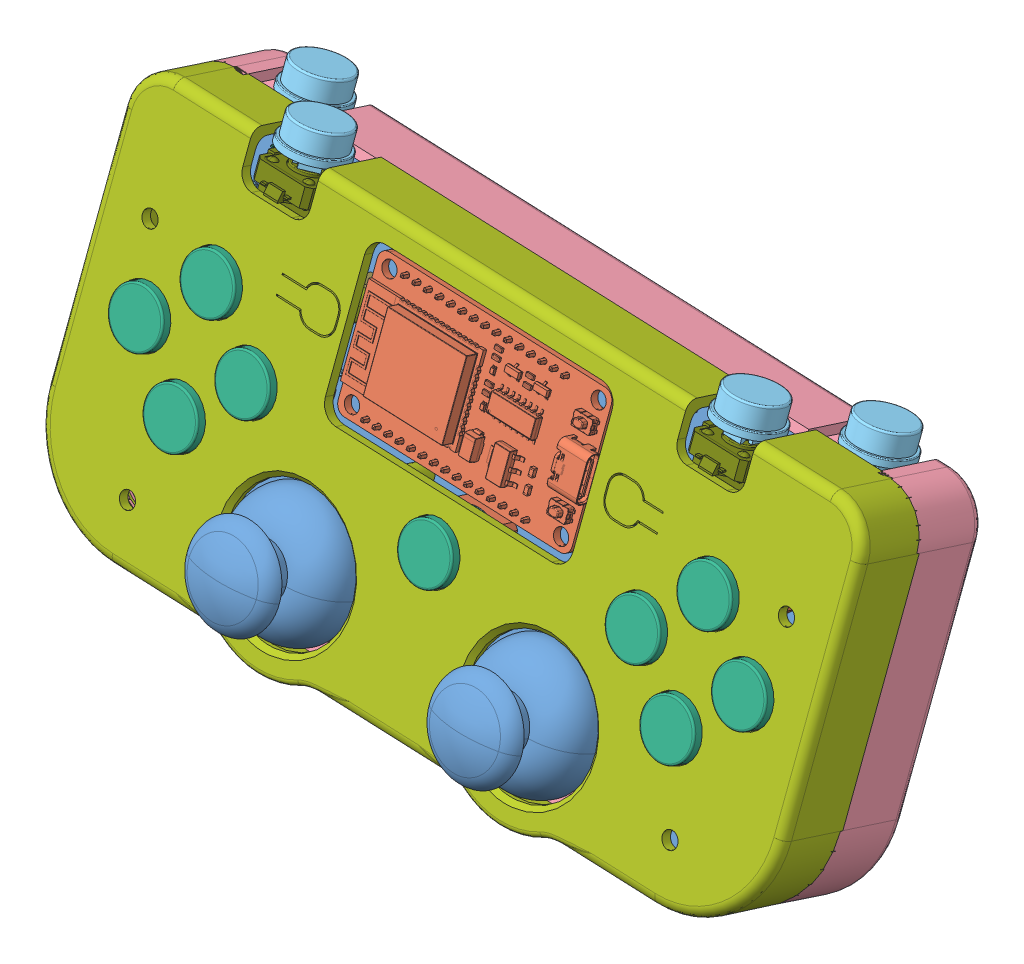
SolidWorks assembly controller, configuration Default. Lengths in mm.
Overall size (166.67 96.35 70.51).
213 component instances, 26 part files, 78 mates.
Components (placement in the parent):
- controller.step-1: controller.step [Default] at (25.4775 3.2443 108.305) x (0.999315 -0.03652 0.006033) z (0.005555 0.30909 0.951017) size (158.62 75.66 29.81)
  - Board.step-1: Board.step [Default] at origin size (158.62 74.17 0.41)
    - Open CASCADE STEP translator 7.5 1.1.1.step-1: Open CASCADE STEP translator 7.5 1.1.1.step [Default] at (0 0 -0.4115) size (158.62 74.17 0.41)
  - SW11.step-1: SW11.step [Default] at origin size (12 13.8 8.01)
    - Switch_Omron_B3F-4000_eec.step-1: Switch_Omron_B3F-4000_eec.step [Default] at (92.7295 35.2468 2.4624) x (0 1 0) z (0 0 1) size (13.8 12 8.01)
      - Omron B3F-4000 1.step-1: Omron B3F-4000 1.step [Default] at (3.1026 -5.4513 -0.4613) size (12 12 5.5)
      - Omron B3F-4000 2.step-1: Omron B3F-4000 2.step [Default] at (3.1026 -5.4513 2.5387) x (-1 0 0) z (0 0 1) size (11 11 0.5)
      - Omron B3F-4000 3.step-1: Omron B3F-4000 3.step [Default] at (3.1026 -5.4513 4.0387) x (1 0 0) z (0 0 -1) size (7.1 7.1 1.5)
      - Omron B3F-4000 4.step-1: Omron B3F-4000 4.step [Default] at (9.5526 -2.4513 -1.9613) x (1 0 0) z (0 -1 0) size (0.9 4 1)
      - Omron B3F-4000 4.step-2: Omron B3F-4000 4.step [Default] at (9.5526 -7.4513 -1.9613) x (1 0 0) z (0 -1 0) size (0.9 4 1)
      - Omron B3F-4000 4_MIR.step-1: Omron B3F-4000 4_MIR.step [Default] at (-3.3474 -2.4513 -1.9613) x (-1 0 0) z (0 1 0) size (0.9 4 1)
      - Omron B3F-4000 4_MIR.step-2: Omron B3F-4000 4_MIR.step [Default] at (-3.3474 -7.4513 -1.9613) x (-1 0 0) z (0 1 0) size (0.9 4 1)
      - Omron B3F-4000 5.step-1: Omron B3F-4000 5.step [Default] at (7.6026 -0.9513 3.0387) size (1.5 1.5 1.2)
      - Omron B3F-4000 5_MIR2.step-1: Omron B3F-4000 5_MIR2.step [Default] at (7.6026 -9.9513 3.0387) x (1 0 0) z (0 0 -1) size (1.5 1.5 1.2)
      - Omron B3F-4000 5_MIR3.step-1: Omron B3F-4000 5_MIR3.step [Default] at (-1.3974 -0.9513 3.0387) x (-1 0 0) z (0 0 -1) size (1.5 1.5 1.2)
      - Omron B3F-4000 5_MIR2_MIR.step-1: Omron B3F-4000 5_MIR2_MIR.step [Default] at (-1.3974 -9.9513 3.0387) x (-1 0 0) z (0 0 1) size (1.5 1.5 1.2)
      - Omron.step-1: Omron.step [Default] at (3.0502 -5.7952 4.0387) size (2.99 0.61 0.02)
  - SW9.step-1: SW9.step [Default] at origin size (6 6 4.5)
    - 7098939168.step-1: 7098939168.step [Default] at (64.389 64.262 0) size (6 6 4.5)
      - Extruded.step-1: Extruded.step [Default] at origin size (6 6 4.5)
  - SW10.step-1: SW10.step [Default] at origin size (6 6 4.5)
    - 7098939168.step-1: 7098939168.step [Default] at (131.953 64.262 0) size (6 6 4.5)
      - Extruded.step-1: Extruded.step [Default] at origin size (6 6 4.5)
  - C5.step-1: C5.step [Default] at origin size (3.81 2.54 11.66)
    - 7094425376.step-1: 7094425376.step [Default] at (34.6711 68.58 -7) size (0.51 0.51 7)
      - Extruded-0.step-1: Extruded-0.step [Default] at origin size (0.51 0.51 7)
    - 7094425376.step-2: 7094425376.step [Default] at (32.1311 68.5801 -7) size (0.51 0.51 7)
      - Extruded-0.step-1: Extruded-0.step [Default] at origin size (0.51 0.51 7)
    - 7098940608.step-1: 7098940608.step [Default] at (33.401 68.58 0) size (3.81 2.54 4.66)
      - Extruded-1.step-1: Extruded-1.step [Default] at origin size (3.81 2.54 4.66)
  - C6.step-1: C6.step [Default] at origin size (3.81 2.54 11.66)
    - 7094425376.step-1: 7094425376.step [Default] at (165.3541 67.31 -7) size (0.51 0.51 7)
      - Extruded-0.step-1: Extruded-0.step [Default] at origin size (0.51 0.51 7)
    - 7094425376.step-2: 7094425376.step [Default] at (162.8141 67.3101 -7) size (0.51 0.51 7)
      - Extruded-0.step-1: Extruded-0.step [Default] at origin size (0.51 0.51 7)
    - 7098940608.step-1: 7098940608.step [Default] at (164.084 67.31 0) size (3.81 2.54 4.66)
      - Extruded-1.step-1: Extruded-1.step [Default] at origin size (3.81 2.54 4.66)
  - S4.step-1: S4.step [Default] at origin size (13.1 13.3 18.3)
    - 6508629744.step-1: 6508629744.step [Default] at (160.742 77.978 -0.4115) x (0 -1 0) z (1 0 0) size (13.3 18.3 13.1)
  - S3.step-1: S3.step [Default] at origin size (13.1 13.3 18.3)
    - 6508631584.step-1: 6508631584.step [Default] at (146.344 77.978 0) x (0 -1 0) z (-1 0 0) size (13.3 18.3 13.1)
  - S2.step-1: S2.step [Default] at origin size (13.1 13.3 18.3)
    - 6508631584.step-1: 6508631584.step [Default] at (49.744 77.978 0) x (0 -1 0) z (-1 0 0) size (13.3 18.3 13.1)
  - S1.step-1: S1.step [Default] at origin size (13.1 13.3 18.3)
    - 6508629744.step-1: 6508629744.step [Default] at (35.346 77.978 -0.4115) x (0 -1 0) z (1 0 0) size (13.3 18.3 13.1)
  - C4.step-1: C4.step [Default] at origin size (4.49 4.49 11.66)
    - 7094425376.step-1: 7094425376.step [Default] at (30.4371 33.138 -7) size (0.51 0.51 7)
      - Extruded-0.step-1: Extruded-0.step [Default] at origin size (0.51 0.51 7)
    - 7094425376.step-2: 7094425376.step [Default] at (28.6411 34.9341 -7) size (0.51 0.51 7)
      - Extruded-0.step-1: Extruded-0.step [Default] at origin size (0.51 0.51 7)
    - 7094424896.step-1: 7094424896.step [Default] at (29.5392 34.036 0) size (4.49 4.49 4.66)
      - Extruded-2.step-1: Extruded-2.step [Default] at origin size (4.49 4.49 4.66)
  - C3.step-1: C3.step [Default] at origin size (4.49 4.49 11.66)
    - 7094425376.step-1: 7094425376.step [Default] at (166.7082 33.9179 -7) size (0.51 0.51 7)
      - Extruded-0.step-1: Extruded-0.step [Default] at origin size (0.51 0.51 7)
    - 7094425376.step-2: 7094425376.step [Default] at (164.9122 32.1219 -7) size (0.51 0.51 7)
      - Extruded-0.step-1: Extruded-0.step [Default] at origin size (0.51 0.51 7)
    - 7098938768.step-1: 7098938768.step [Default] at (165.8102 33.02 0) size (4.49 4.49 4.66)
      - Extruded-3.step-1: Extruded-3.step [Default] at origin size (4.49 4.49 4.66)
  - C2.step-1: C2.step [Default] at origin size (4.49 4.49 11.66)
    - 7094425376.step-1: 7094425376.step [Default] at (55.4293 60.9781 -7) size (0.51 0.51 7)
      - Extruded-0.step-1: Extruded-0.step [Default] at origin size (0.51 0.51 7)
    - 7094425376.step-2: 7094425376.step [Default] at (57.2253 59.182 -7) size (0.51 0.51 7)
      - Extruded-0.step-1: Extruded-0.step [Default] at origin size (0.51 0.51 7)
    - 7094424896.step-1: 7094424896.step [Default] at (56.3272 60.08 0) size (4.49 4.49 4.66)
      - Extruded-2.step-1: Extruded-2.step [Default] at origin size (4.49 4.49 4.66)
  - C1.step-1: C1.step [Default] at origin size (4.49 4.49 11.66)
    - 7094425376.step-1: 7094425376.step [Default] at (139.5122 58.4111 -7) size (0.51 0.51 7)
      - Extruded-0.step-1: Extruded-0.step [Default] at origin size (0.51 0.51 7)
    - 7094425376.step-2: 7094425376.step [Default] at (141.3083 60.2071 -7) size (0.51 0.51 7)
      - Extruded-0.step-1: Extruded-0.step [Default] at origin size (0.51 0.51 7)
    - 7098938768.step-1: 7098938768.step [Default] at (140.4102 59.309 0) size (4.49 4.49 4.66)
      - Extruded-3.step-1: Extruded-3.step [Default] at origin size (4.49 4.49 4.66)
  - SW1.step-1: SW1.step [Default] at origin size (18.24 18.24 8.01)
    - Switch_Omron_B3F-4000_eec.step-1: Switch_Omron_B3F-4000_eec.step [Default] at (48.6404 48.2596 2.4624) x (0.707107 0.707107 0) z (0 0 1) size (13.8 12 8.01)
      - Omron B3F-4000 1.step-1: Omron B3F-4000 1.step [Default] at (3.1026 -5.4513 -0.4613) size (12 12 5.5)
      - Omron B3F-4000 2.step-1: Omron B3F-4000 2.step [Default] at (3.1026 -5.4513 2.5387) x (-1 0 0) z (0 0 1) size (11 11 0.5)
      - Omron B3F-4000 3.step-1: Omron B3F-4000 3.step [Default] at (3.1026 -5.4513 4.0387) x (1 0 0) z (0 0 -1) size (7.1 7.1 1.5)
      - Omron B3F-4000 4.step-1: Omron B3F-4000 4.step [Default] at (9.5526 -2.4513 -1.9613) x (1 0 0) z (0 -1 0) size (0.9 4 1)
      - Omron B3F-4000 4.step-2: Omron B3F-4000 4.step [Default] at (9.5526 -7.4513 -1.9613) x (1 0 0) z (0 -1 0) size (0.9 4 1)
      - Omron B3F-4000 4_MIR.step-1: Omron B3F-4000 4_MIR.step [Default] at (-3.3474 -2.4513 -1.9613) x (-1 0 0) z (0 1 0) size (0.9 4 1)
      - Omron B3F-4000 4_MIR.step-2: Omron B3F-4000 4_MIR.step [Default] at (-3.3474 -7.4513 -1.9613) x (-1 0 0) z (0 1 0) size (0.9 4 1)
      - Omron B3F-4000 5.step-1: Omron B3F-4000 5.step [Default] at (7.6026 -0.9513 3.0387) size (1.5 1.5 1.2)
      - Omron B3F-4000 5_MIR2.step-1: Omron B3F-4000 5_MIR2.step [Default] at (7.6026 -9.9513 3.0387) x (1 0 0) z (0 0 -1) size (1.5 1.5 1.2)
      - Omron B3F-4000 5_MIR3.step-1: Omron B3F-4000 5_MIR3.step [Default] at (-1.3974 -0.9513 3.0387) x (-1 0 0) z (0 0 -1) size (1.5 1.5 1.2)
      - Omron B3F-4000 5_MIR2_MIR.step-1: Omron B3F-4000 5_MIR2_MIR.step [Default] at (-1.3974 -9.9513 3.0387) x (-1 0 0) z (0 0 1) size (1.5 1.5 1.2)
      - Omron.step-1: Omron.step [Default] at (3.0502 -5.7952 4.0387) size (2.99 0.61 0.02)
  - SW2.step-1: SW2.step [Default] at origin size (18.24 18.24 8.01)
    - Switch_Omron_B3F-4000_eec.step-1: Switch_Omron_B3F-4000_eec.step [Default] at (36.8294 60.0706 2.4624) x (0.707107 0.707107 0) z (0 0 1) size (13.8 12 8.01)
      - Omron B3F-4000 1.step-1: Omron B3F-4000 1.step [Default] at (3.1026 -5.4513 -0.4613) size (12 12 5.5)
      - Omron B3F-4000 2.step-1: Omron B3F-4000 2.step [Default] at (3.1026 -5.4513 2.5387) x (-1 0 0) z (0 0 1) size (11 11 0.5)
      - Omron B3F-4000 3.step-1: Omron B3F-4000 3.step [Default] at (3.1026 -5.4513 4.0387) x (1 0 0) z (0 0 -1) size (7.1 7.1 1.5)
      - Omron B3F-4000 4.step-1: Omron B3F-4000 4.step [Default] at (9.5526 -2.4513 -1.9613) x (1 0 0) z (0 -1 0) size (0.9 4 1)
      - Omron B3F-4000 4.step-2: Omron B3F-4000 4.step [Default] at (9.5526 -7.4513 -1.9613) x (1 0 0) z (0 -1 0) size (0.9 4 1)
      - Omron B3F-4000 4_MIR.step-1: Omron B3F-4000 4_MIR.step [Default] at (-3.3474 -2.4513 -1.9613) x (-1 0 0) z (0 1 0) size (0.9 4 1)
      - Omron B3F-4000 4_MIR.step-2: Omron B3F-4000 4_MIR.step [Default] at (-3.3474 -7.4513 -1.9613) x (-1 0 0) z (0 1 0) size (0.9 4 1)
      - Omron B3F-4000 5.step-1: Omron B3F-4000 5.step [Default] at (7.6026 -0.9513 3.0387) size (1.5 1.5 1.2)
      - Omron B3F-4000 5_MIR2.step-1: Omron B3F-4000 5_MIR2.step [Default] at (7.6026 -9.9513 3.0387) x (1 0 0) z (0 0 -1) size (1.5 1.5 1.2)
      - Omron B3F-4000 5_MIR3.step-1: Omron B3F-4000 5_MIR3.step [Default] at (-1.3974 -0.9513 3.0387) x (-1 0 0) z (0 0 -1) size (1.5 1.5 1.2)
      - Omron B3F-4000 5_MIR2_MIR.step-1: Omron B3F-4000 5_MIR2_MIR.step [Default] at (-1.3974 -9.9513 3.0387) x (-1 0 0) z (0 0 1) size (1.5 1.5 1.2)
      - Omron.step-1: Omron.step [Default] at (3.0502 -5.7952 4.0387) size (2.99 0.61 0.02)
  - SW3.step-1: SW3.step [Default] at origin size (18.24 18.24 8.01)
    - Switch_Omron_B3F-4000_eec.step-1: Switch_Omron_B3F-4000_eec.step [Default] at (25.0184 48.2596 2.4624) x (0.707107 0.707107 0) z (0 0 1) size (13.8 12 8.01)
      - Omron B3F-4000 1.step-1: Omron B3F-4000 1.step [Default] at (3.1026 -5.4513 -0.4613) size (12 12 5.5)
      - Omron B3F-4000 2.step-1: Omron B3F-4000 2.step [Default] at (3.1026 -5.4513 2.5387) x (-1 0 0) z (0 0 1) size (11 11 0.5)
      - Omron B3F-4000 3.step-1: Omron B3F-4000 3.step [Default] at (3.1026 -5.4513 4.0387) x (1 0 0) z (0 0 -1) size (7.1 7.1 1.5)
      - Omron B3F-4000 4.step-1: Omron B3F-4000 4.step [Default] at (9.5526 -2.4513 -1.9613) x (1 0 0) z (0 -1 0) size (0.9 4 1)
      - Omron B3F-4000 4.step-2: Omron B3F-4000 4.step [Default] at (9.5526 -7.4513 -1.9613) x (1 0 0) z (0 -1 0) size (0.9 4 1)
      - Omron B3F-4000 4_MIR.step-1: Omron B3F-4000 4_MIR.step [Default] at (-3.3474 -2.4513 -1.9613) x (-1 0 0) z (0 1 0) size (0.9 4 1)
      - Omron B3F-4000 4_MIR.step-2: Omron B3F-4000 4_MIR.step [Default] at (-3.3474 -7.4513 -1.9613) x (-1 0 0) z (0 1 0) size (0.9 4 1)
      - Omron B3F-4000 5.step-1: Omron B3F-4000 5.step [Default] at (7.6026 -0.9513 3.0387) size (1.5 1.5 1.2)
      - Omron B3F-4000 5_MIR2.step-1: Omron B3F-4000 5_MIR2.step [Default] at (7.6026 -9.9513 3.0387) x (1 0 0) z (0 0 -1) size (1.5 1.5 1.2)
      - Omron B3F-4000 5_MIR3.step-1: Omron B3F-4000 5_MIR3.step [Default] at (-1.3974 -0.9513 3.0387) x (-1 0 0) z (0 0 -1) size (1.5 1.5 1.2)
      - Omron B3F-4000 5_MIR2_MIR.step-1: Omron B3F-4000 5_MIR2_MIR.step [Default] at (-1.3974 -9.9513 3.0387) x (-1 0 0) z (0 0 1) size (1.5 1.5 1.2)
      - Omron.step-1: Omron.step [Default] at (3.0502 -5.7952 4.0387) size (2.99 0.61 0.02)
  - SW4.step-1: SW4.step [Default] at origin size (18.24 18.24 8.01)
    - Switch_Omron_B3F-4000_eec.step-1: Switch_Omron_B3F-4000_eec.step [Default] at (36.8294 36.4486 2.4624) x (0.707107 0.707107 0) z (0 0 1) size (13.8 12 8.01)
      - Omron B3F-4000 1.step-1: Omron B3F-4000 1.step [Default] at (3.1026 -5.4513 -0.4613) size (12 12 5.5)
      - Omron B3F-4000 2.step-1: Omron B3F-4000 2.step [Default] at (3.1026 -5.4513 2.5387) x (-1 0 0) z (0 0 1) size (11 11 0.5)
      - Omron B3F-4000 3.step-1: Omron B3F-4000 3.step [Default] at (3.1026 -5.4513 4.0387) x (1 0 0) z (0 0 -1) size (7.1 7.1 1.5)
      - Omron B3F-4000 4.step-1: Omron B3F-4000 4.step [Default] at (9.5526 -2.4513 -1.9613) x (1 0 0) z (0 -1 0) size (0.9 4 1)
      - Omron B3F-4000 4.step-2: Omron B3F-4000 4.step [Default] at (9.5526 -7.4513 -1.9613) x (1 0 0) z (0 -1 0) size (0.9 4 1)
      - Omron B3F-4000 4_MIR.step-1: Omron B3F-4000 4_MIR.step [Default] at (-3.3474 -2.4513 -1.9613) x (-1 0 0) z (0 1 0) size (0.9 4 1)
      - Omron B3F-4000 4_MIR.step-2: Omron B3F-4000 4_MIR.step [Default] at (-3.3474 -7.4513 -1.9613) x (-1 0 0) z (0 1 0) size (0.9 4 1)
      - Omron B3F-4000 5.step-1: Omron B3F-4000 5.step [Default] at (7.6026 -0.9513 3.0387) size (1.5 1.5 1.2)
      - Omron B3F-4000 5_MIR2.step-1: Omron B3F-4000 5_MIR2.step [Default] at (7.6026 -9.9513 3.0387) x (1 0 0) z (0 0 -1) size (1.5 1.5 1.2)
      - Omron B3F-4000 5_MIR3.step-1: Omron B3F-4000 5_MIR3.step [Default] at (-1.3974 -0.9513 3.0387) x (-1 0 0) z (0 0 -1) size (1.5 1.5 1.2)
      - Omron B3F-4000 5_MIR2_MIR.step-1: Omron B3F-4000 5_MIR2_MIR.step [Default] at (-1.3974 -9.9513 3.0387) x (-1 0 0) z (0 0 1) size (1.5 1.5 1.2)
      - Omron.step-1: Omron.step [Default] at (3.0502 -5.7952 4.0387) size (2.99 0.61 0.02)
  - SW8.step-1: SW8.step [Default] at origin size (18.24 18.24 8.01)
    - Switch_Omron_B3F-4000_eec.step-1: Switch_Omron_B3F-4000_eec.step [Default] at (147.1924 36.4486 2.4624) x (0.707107 0.707107 0) z (0 0 1) size (13.8 12 8.01)
      - Omron B3F-4000 1.step-1: Omron B3F-4000 1.step [Default] at (3.1026 -5.4513 -0.4613) size (12 12 5.5)
      - Omron B3F-4000 2.step-1: Omron B3F-4000 2.step [Default] at (3.1026 -5.4513 2.5387) x (-1 0 0) z (0 0 1) size (11 11 0.5)
      - Omron B3F-4000 3.step-1: Omron B3F-4000 3.step [Default] at (3.1026 -5.4513 4.0387) x (1 0 0) z (0 0 -1) size (7.1 7.1 1.5)
      - Omron B3F-4000 4.step-1: Omron B3F-4000 4.step [Default] at (9.5526 -2.4513 -1.9613) x (1 0 0) z (0 -1 0) size (0.9 4 1)
      - Omron B3F-4000 4.step-2: Omron B3F-4000 4.step [Default] at (9.5526 -7.4513 -1.9613) x (1 0 0) z (0 -1 0) size (0.9 4 1)
      - Omron B3F-4000 4_MIR.step-1: Omron B3F-4000 4_MIR.step [Default] at (-3.3474 -2.4513 -1.9613) x (-1 0 0) z (0 1 0) size (0.9 4 1)
      - Omron B3F-4000 4_MIR.step-2: Omron B3F-4000 4_MIR.step [Default] at (-3.3474 -7.4513 -1.9613) x (-1 0 0) z (0 1 0) size (0.9 4 1)
      - Omron B3F-4000 5.step-1: Omron B3F-4000 5.step [Default] at (7.6026 -0.9513 3.0387) size (1.5 1.5 1.2)
      - Omron B3F-4000 5_MIR2.step-1: Omron B3F-4000 5_MIR2.step [Default] at (7.6026 -9.9513 3.0387) x (1 0 0) z (0 0 -1) size (1.5 1.5 1.2)
      - Omron B3F-4000 5_MIR3.step-1: Omron B3F-4000 5_MIR3.step [Default] at (-1.3974 -0.9513 3.0387) x (-1 0 0) z (0 0 -1) size (1.5 1.5 1.2)
      - Omron B3F-4000 5_MIR2_MIR.step-1: Omron B3F-4000 5_MIR2_MIR.step [Default] at (-1.3974 -9.9513 3.0387) x (-1 0 0) z (0 0 1) size (1.5 1.5 1.2)
      - Omron.step-1: Omron.step [Default] at (3.0502 -5.7952 4.0387) size (2.99 0.61 0.02)
  - SW7.step-1: SW7.step [Default] at origin size (18.24 18.24 8.01)
    - Switch_Omron_B3F-4000_eec.step-1: Switch_Omron_B3F-4000_eec.step [Default] at (135.3813 48.2596 2.4624) x (0.707107 0.707107 0) z (0 0 1) size (13.8 12 8.01)
      - Omron B3F-4000 1.step-1: Omron B3F-4000 1.step [Default] at (3.1026 -5.4513 -0.4613) size (12 12 5.5)
      - Omron B3F-4000 2.step-1: Omron B3F-4000 2.step [Default] at (3.1026 -5.4513 2.5387) x (-1 0 0) z (0 0 1) size (11 11 0.5)
      - Omron B3F-4000 3.step-1: Omron B3F-4000 3.step [Default] at (3.1026 -5.4513 4.0387) x (1 0 0) z (0 0 -1) size (7.1 7.1 1.5)
      - Omron B3F-4000 4.step-1: Omron B3F-4000 4.step [Default] at (9.5526 -2.4513 -1.9613) x (1 0 0) z (0 -1 0) size (0.9 4 1)
      - Omron B3F-4000 4.step-2: Omron B3F-4000 4.step [Default] at (9.5526 -7.4513 -1.9613) x (1 0 0) z (0 -1 0) size (0.9 4 1)
      - Omron B3F-4000 4_MIR.step-1: Omron B3F-4000 4_MIR.step [Default] at (-3.3474 -2.4513 -1.9613) x (-1 0 0) z (0 1 0) size (0.9 4 1)
      - Omron B3F-4000 4_MIR.step-2: Omron B3F-4000 4_MIR.step [Default] at (-3.3474 -7.4513 -1.9613) x (-1 0 0) z (0 1 0) size (0.9 4 1)
      - Omron B3F-4000 5.step-1: Omron B3F-4000 5.step [Default] at (7.6026 -0.9513 3.0387) size (1.5 1.5 1.2)
      - Omron B3F-4000 5_MIR2.step-1: Omron B3F-4000 5_MIR2.step [Default] at (7.6026 -9.9513 3.0387) x (1 0 0) z (0 0 -1) size (1.5 1.5 1.2)
      - Omron B3F-4000 5_MIR3.step-1: Omron B3F-4000 5_MIR3.step [Default] at (-1.3974 -0.9513 3.0387) x (-1 0 0) z (0 0 -1) size (1.5 1.5 1.2)
      - Omron B3F-4000 5_MIR2_MIR.step-1: Omron B3F-4000 5_MIR2_MIR.step [Default] at (-1.3974 -9.9513 3.0387) x (-1 0 0) z (0 0 1) size (1.5 1.5 1.2)
      - Omron.step-1: Omron.step [Default] at (3.0502 -5.7952 4.0387) size (2.99 0.61 0.02)
  - SW6.step-1: SW6.step [Default] at origin size (18.24 18.24 8.01)
    - Switch_Omron_B3F-4000_eec.step-1: Switch_Omron_B3F-4000_eec.step [Default] at (147.1924 60.0706 2.4624) x (0.707107 0.707107 0) z (0 0 1) size (13.8 12 8.01)
      - Omron B3F-4000 1.step-1: Omron B3F-4000 1.step [Default] at (3.1026 -5.4513 -0.4613) size (12 12 5.5)
      - Omron B3F-4000 2.step-1: Omron B3F-4000 2.step [Default] at (3.1026 -5.4513 2.5387) x (-1 0 0) z (0 0 1) size (11 11 0.5)
      - Omron B3F-4000 3.step-1: Omron B3F-4000 3.step [Default] at (3.1026 -5.4513 4.0387) x (1 0 0) z (0 0 -1) size (7.1 7.1 1.5)
      - Omron B3F-4000 4.step-1: Omron B3F-4000 4.step [Default] at (9.5526 -2.4513 -1.9613) x (1 0 0) z (0 -1 0) size (0.9 4 1)
      - Omron B3F-4000 4.step-2: Omron B3F-4000 4.step [Default] at (9.5526 -7.4513 -1.9613) x (1 0 0) z (0 -1 0) size (0.9 4 1)
      - Omron B3F-4000 4_MIR.step-1: Omron B3F-4000 4_MIR.step [Default] at (-3.3474 -2.4513 -1.9613) x (-1 0 0) z (0 1 0) size (0.9 4 1)
      - Omron B3F-4000 4_MIR.step-2: Omron B3F-4000 4_MIR.step [Default] at (-3.3474 -7.4513 -1.9613) x (-1 0 0) z (0 1 0) size (0.9 4 1)
      - Omron B3F-4000 5.step-1: Omron B3F-4000 5.step [Default] at (7.6026 -0.9513 3.0387) size (1.5 1.5 1.2)
      - Omron B3F-4000 5_MIR2.step-1: Omron B3F-4000 5_MIR2.step [Default] at (7.6026 -9.9513 3.0387) x (1 0 0) z (0 0 -1) size (1.5 1.5 1.2)
      - Omron B3F-4000 5_MIR3.step-1: Omron B3F-4000 5_MIR3.step [Default] at (-1.3974 -0.9513 3.0387) x (-1 0 0) z (0 0 -1) size (1.5 1.5 1.2)
      - Omron B3F-4000 5_MIR2_MIR.step-1: Omron B3F-4000 5_MIR2_MIR.step [Default] at (-1.3974 -9.9513 3.0387) x (-1 0 0) z (0 0 1) size (1.5 1.5 1.2)
      - Omron.step-1: Omron.step [Default] at (3.0502 -5.7952 4.0387) size (2.99 0.61 0.02)
  - SW5.step-1: SW5.step [Default] at origin size (18.24 18.24 8.01)
    - Switch_Omron_B3F-4000_eec.step-1: Switch_Omron_B3F-4000_eec.step [Default] at (159.0034 48.2596 2.4624) x (0.707107 0.707107 0) z (0 0 1) size (13.8 12 8.01)
      - Omron B3F-4000 1.step-1: Omron B3F-4000 1.step [Default] at (3.1026 -5.4513 -0.4613) size (12 12 5.5)
      - Omron B3F-4000 2.step-1: Omron B3F-4000 2.step [Default] at (3.1026 -5.4513 2.5387) x (-1 0 0) z (0 0 1) size (11 11 0.5)
      - Omron B3F-4000 3.step-1: Omron B3F-4000 3.step [Default] at (3.1026 -5.4513 4.0387) x (1 0 0) z (0 0 -1) size (7.1 7.1 1.5)
      - Omron B3F-4000 4.step-1: Omron B3F-4000 4.step [Default] at (9.5526 -2.4513 -1.9613) x (1 0 0) z (0 -1 0) size (0.9 4 1)
      - Omron B3F-4000 4.step-2: Omron B3F-4000 4.step [Default] at (9.5526 -7.4513 -1.9613) x (1 0 0) z (0 -1 0) size (0.9 4 1)
      - Omron B3F-4000 4_MIR.step-1: Omron B3F-4000 4_MIR.step [Default] at (-3.3474 -2.4513 -1.9613) x (-1 0 0) z (0 1 0) size (0.9 4 1)
      - Omron B3F-4000 4_MIR.step-2: Omron B3F-4000 4_MIR.step [Default] at (-3.3474 -7.4513 -1.9613) x (-1 0 0) z (0 1 0) size (0.9 4 1)
      - Omron B3F-4000 5.step-1: Omron B3F-4000 5.step [Default] at (7.6026 -0.9513 3.0387) size (1.5 1.5 1.2)
      - Omron B3F-4000 5_MIR2.step-1: Omron B3F-4000 5_MIR2.step [Default] at (7.6026 -9.9513 3.0387) x (1 0 0) z (0 0 -1) size (1.5 1.5 1.2)
      - Omron B3F-4000 5_MIR3.step-1: Omron B3F-4000 5_MIR3.step [Default] at (-1.3974 -0.9513 3.0387) x (-1 0 0) z (0 0 -1) size (1.5 1.5 1.2)
      - Omron B3F-4000 5_MIR2_MIR.step-1: Omron B3F-4000 5_MIR2_MIR.step [Default] at (-1.3974 -9.9513 3.0387) x (-1 0 0) z (0 0 1) size (1.5 1.5 1.2)
      - Omron.step-1: Omron.step [Default] at (3.0502 -5.7952 4.0387) size (2.99 0.61 0.02)
- COM-09032-1: COM-09032 [Default] at (97.4277 22.5889 101.5976) x (0.999315 -0.03652 0.006033) z (-0.036596 -0.950331 0.309081) size (26.67 34.67 27.62)
- COM-09032-2: COM-09032 [Default] at (151.2136 20.6099 101.9266) x (0.999315 -0.03652 0.006033) z (-0.036596 -0.950331 0.309081) size (26.67 34.67 27.62)
- esp32_30pin-1: esp32_30pin [По умолчанию] at (148.2005 52.2986 104.8892) x (0.036596 0.950331 -0.309081) z (0.005555 0.30909 0.951017) size (29 52.96 13.53)
- powerboost 1000c.f3d v3-1: powerboost 1000c.f3d v3 [Default] at (151.8493 9.8112 109.6265) x (0.036596 0.950331 -0.309081) z (-0.005555 -0.30909 -0.951017) size (36.64 22.86 4.38)
- Bottom_plate_R3-1: Bottom_plate_R3 [Default] at (45.1984 24.5346 86.1165) x (0.999315 -0.03652 0.006033) z (-0.036596 -0.950331 0.309081) size (163.63 15.6 81.83)
- 12mm Push Button Cap-1: 12mm Push Button Cap [Default] at (179.9154 32.315 103.4225) x (0.640311 -0.731594 0.234035) z (-0.768096 -0.607647 0.201977) size (13 8.2 13)
- 12mm Push Button Cap-2: 12mm Push Button Cap [Default] at (180.7799 54.7638 96.1214) x (0.640311 -0.731594 0.234035) z (-0.768096 -0.607647 0.201977) size (13 8.2 13)
- 12mm Push Button Cap-3: 12mm Push Button Cap [Default] at (168.5447 43.9708 99.7007) x (0.640311 -0.731594 0.234035) z (-0.768096 -0.607647 0.201977) size (13 8.2 13)
- 12mm Push Button Cap-4: 12mm Push Button Cap [Default] at (192.1505 43.1081 99.8432) x (0.191146 0.933167 -0.304405) z (0.981546 -0.183474 0.053898) size (13 8.2 13)
- 12mm Push Button Cap-5: 12mm Push Button Cap [Default] at (125.0234 37.7106 101.9895) x (0.551571 -0.794223 0.254909) z (-0.834109 -0.523138 0.174897) size (13 8.2 13)
- 12mm Push Button Cap TALL-1: 12mm Push Button Cap TALL [Default] at (192.1505 43.1081 99.8432) x (-0.613772 -0.749763 0.247265) z (-0.789464 0.585081 -0.185546) size (13 12.9 13)
- top_plate-1: top_plate [Default] at (203.8731 27.5232 114.0932) x (-0.999315 0.03652 -0.006033) z (-0.036596 -0.950331 0.309081) size (163.63 18.26 81.83)
- 12mm Push Button Cap-6: 12mm Push Button Cap [Default] at (58.2574 48.0013 99.0349) x (0.7195 -0.661708 0.210859) z (-0.69447 -0.683086 0.226066) size (13 8.2 13)
- 12mm Push Button Cap-7: 12mm Push Button Cap [Default] at (70.4925 58.7943 95.4556) x (0.640311 -0.731594 0.234035) z (-0.768096 -0.607647 0.201977) size (13 8.2 13)
- 12mm Push Button Cap-8: 12mm Push Button Cap [Default] at (69.628 36.3456 102.7567) x (0.640311 -0.731594 0.234035) z (-0.768096 -0.607647 0.201977) size (13 8.2 13)
- 12mm Push Button Cap-9: 12mm Push Button Cap [Default] at (81.8632 47.1386 99.1774) x (0.640311 -0.731594 0.234035) z (-0.768096 -0.607647 0.201977) size (13 8.2 13)
- 12mm Push Button Cap TALL-6: 12mm Push Button Cap TALL [Default] at (180.7799 54.7638 96.1214) x (0.113687 0.94467 -0.307691) z (0.993501 -0.109828 0.029892) size (13 12.9 13)
- 12mm Push Button Cap TALL-7: 12mm Push Button Cap TALL [Default] at (125.0234 37.7106 101.9895) x (-0.448672 -0.84916 0.278606) z (-0.893679 0.428242 -0.133963) size (13 12.9 13)
- 12mm Push Button Cap TALL-8: 12mm Push Button Cap TALL [Default] at (58.2574 48.0013 99.0349) x (-0.502403 -0.821427 0.269906) z (-0.864616 0.479293 -0.150725) size (13 12.9 13)
- 12mm Push Button Cap TALL-9: 12mm Push Button Cap TALL [Default] at (69.628 36.3456 102.7567) x (-0.776873 -0.597476 0.198723) z (-0.629633 0.739923 -0.236805) size (13 12.9 13)
- 12mm Push Button Cap TALL-10: 12mm Push Button Cap TALL [Default] at (168.5447 43.9708 99.7007) x (-0.613772 -0.749763 0.247265) z (-0.789464 0.585081 -0.185546) size (13 12.9 13)
- 12mm Push Button Cap TALL-11: 12mm Push Button Cap TALL [Default] at (179.9154 32.315 103.4225) x (-0.613772 -0.749763 0.247265) z (-0.789464 0.585081 -0.185546) size (13 12.9 13)
- 12mm Push Button Cap TALL-12: 12mm Push Button Cap TALL [Default] at (70.4925 58.7943 95.4556) x (-0.78112 -0.592451 0.197115) z (-0.624357 0.743953 -0.238145) size (13 12.9 13)
- 12mm Push Button Cap TALL-13: 12mm Push Button Cap TALL [Default] at (81.8632 47.1386 99.1774) x (-0.613772 -0.749763 0.247265) z (-0.789464 0.585081 -0.185546) size (13 12.9 13)
- 12mm Push Button Cap-10: 12mm Push Button Cap [Default] at (174.8391 80.1008 90.3398) x (0.005555 0.30909 0.951017) z (-0.999315 0.03652 -0.006033) size (13 8.2 13)
- 12mm Push Button Cap-11: 12mm Push Button Cap [Default] at (189.1416 74.8115 75.7701) x (0.285665 -0.30633 -0.908051) z (0.95763 0.055062 0.282687) size (13 8.2 13)
- 12mm Push Button Cap-12: 12mm Push Button Cap [Default] at (63.8315 79.391 75.0136) x (0.654 0.211082 0.72645) z (-0.755609 0.228724 0.613792) size (13 8.2 13)
- 12mm Push Button Cap-13: 12mm Push Button Cap [Default] at (78.3053 83.6287 89.757) x (0.680165 0.202908 0.704417) z (-0.732145 0.236005 0.638957) size (13 8.2 13)
Mates (geometry in assembly coordinates):
- Coincident2: coincident anti-aligned: plane of controller.step-1/Board.step-1/Open CASCADE STEP translator 7.5 1.1.1.step-1 through (125.235 44.2553 94.3933) normal (0.005555 0.30909 0.951017); plane of COM-09032-1 through (97.4277 22.5889 101.5976) normal (-0.005555 -0.30909 -0.951017)
- Parallel6: parallel aligned: plane of controller.step-1/Board.step-1/Open CASCADE STEP translator 7.5 1.1.1.step-1 through (184.0564 5.6611 106.1606) normal (-0.036596 -0.950331 0.309081); plane of COM-09032-1 through (96.5277 11.5931 105.1766) normal (-0.036596 -0.950331 0.309081)
- Distance1: distance = 2.7383 mm aligned: plane of COM-09032-1 through (96.5277 11.5931 105.1766) normal (-0.036596 -0.950331 0.309081); plane of controller.step-1/Board.step-1/Open CASCADE STEP translator 7.5 1.1.1.step-1 through (184.0564 5.6611 106.1606) normal (-0.036596 -0.950331 0.309081)
- Distance3: distance = 44.4205 mm aligned: plane of COM-09032-1 through (89.0631 7.9437 82.7993) normal (-0.999315 0.03652 -0.006033); plane of controller.step-1/Board.step-1/Open CASCADE STEP translator 7.5 1.1.1.step-1 through (45.2762 28.8622 99.4306) normal (-0.999315 0.03652 -0.006033)
- Coincident17: coincident anti-aligned: plane of controller.step-1/Board.step-1/Open CASCADE STEP translator 7.5 1.1.1.step-1 through (125.235 44.2553 94.3933) normal (0.005555 0.30909 0.951017); plane of COM-09032-2 through (151.2136 20.6099 101.9266) normal (-0.005555 -0.30909 -0.951017)
- Parallel8: parallel: line of controller.step-1/Board.step-1/Open CASCADE STEP translator 7.5 1.1.1.step-1 through (184.0564 5.6611 106.1606) axis (-0.999315 0.03652 -0.006033); plane of COM-09032-2 through (150.3136 9.6141 105.5056) normal (-0.036596 -0.950331 0.309081)
- Distance4: distance = 44.5042 mm aligned: plane of COM-09032-2 through (158.7131 5.3849 83.2241) normal (0.999315 -0.03652 0.006033); plane of controller.step-1/Board.step-1/Open CASCADE STEP translator 7.5 1.1.1.step-1 through (205.5752 69.415 85.3143) normal (0.999315 -0.03652 0.006033)
- Distance5: distance = 2.7243 mm aligned: plane of COM-09032-2 through (150.3136 9.6141 105.5056) normal (-0.036596 -0.950331 0.309081); plane of controller.step-1/Board.step-1/Open CASCADE STEP translator 7.5 1.1.1.step-1 through (184.0564 5.6611 106.1606) normal (-0.036596 -0.950331 0.309081)
- Parallel9: parallel anti-aligned: plane of controller.step-1/Board.step-1/Open CASCADE STEP translator 7.5 1.1.1.step-1 through (125.235 44.2553 94.3933) normal (0.005555 0.30909 0.951017); plane of esp32_30pin-1 through (125.2811 64.1247 99.5019) normal (-0.005555 -0.30909 -0.951017)
- Parallel10: parallel aligned: plane of controller.step-1/Board.step-1/Open CASCADE STEP translator 7.5 1.1.1.step-1 through (53.639 81.0107 82.433) normal (0.036596 0.950331 -0.309081); plane of esp32_30pin-1 through (149.7954 77.028 95.165) normal (0.036596 0.950331 -0.309081)
- Parallel11: parallel aligned: plane of controller.step-1/Board.step-1/Open CASCADE STEP translator 7.5 1.1.1.step-1 through (45.2762 28.8622 99.4306) normal (-0.999315 0.03652 -0.006033); plane of esp32_30pin-1 through (99.7565 76.9533 95.4816) normal (-0.999315 0.03652 -0.006033)
- Distance10: distance = 53.9602 mm aligned: plane of esp32_30pin-1 through (150.8059 51.296 103.5223) normal (0.999315 -0.03652 0.006033); plane of controller.step-1/Board.step-1/Open CASCADE STEP translator 7.5 1.1.1.step-1 through (205.5752 69.415 85.3143) normal (0.999315 -0.03652 0.006033)
- Distance11: distance = 4.2011 mm aligned: plane of esp32_30pin-1 through (149.7954 77.028 95.165) normal (0.036596 0.950331 -0.309081); plane of controller.step-1/Board.step-1/Open CASCADE STEP translator 7.5 1.1.1.step-1 through (53.639 81.0107 82.433) normal (0.036596 0.950331 -0.309081)
- Parallel15: parallel aligned: plane of controller.step-1/Board.step-1/Open CASCADE STEP translator 7.5 1.1.1.step-1 through (125.2328 44.1282 94.002) normal (-0.005555 -0.30909 -0.951017); plane of powerboost 1000c.f3d v3-1 through (124.3289 22.2845 91.0122) normal (-0.005555 -0.30909 -0.951017)
- Parallel18: parallel aligned: plane of controller.step-1/Board.step-1/Open CASCADE STEP translator 7.5 1.1.1.step-1 through (184.0564 5.6611 106.1606) normal (-0.036596 -0.950331 0.309081); plane of powerboost 1000c.f3d v3-1 through (135.0976 5.1606 98.1972) normal (-0.036596 -0.950331 0.309081)
- Distance13: distance = 11 mm anti-aligned: plane of esp32_30pin-1 through (125.2811 64.1247 99.5019) normal (-0.005555 -0.30909 -0.951017); plane of controller.step-1/Board.step-1/Open CASCADE STEP translator 7.5 1.1.1.step-1 through (125.235 44.2553 94.3933) normal (0.005555 0.30909 0.951017)
- Parallel19: parallel anti-aligned: plane of controller.step-1/Board.step-1/Open CASCADE STEP translator 7.5 1.1.1.step-1 through (125.2328 44.1282 94.002) normal (-0.005555 -0.30909 -0.951017); plane of Part1-1 through (64.2478 24.457 88.1335) normal (0.005555 0.30909 0.951017)
- Parallel20: parallel anti-aligned: plane of controller.step-1/Board.step-1/Open CASCADE STEP translator 7.5 1.1.1.step-1 through (53.639 81.0107 82.433) normal (0.036596 0.950331 -0.309081); plane of Part1-1 through (199.4047 71.8293 69.8446) normal (-0.036596 -0.950331 0.309081)
- Parallel21: parallel aligned: plane of controller.step-1/Board.step-1/Open CASCADE STEP translator 7.5 1.1.1.step-1 through (205.5752 69.415 85.3143) normal (0.999315 -0.03652 0.006033); plane of Part1-1 through (206.2136 18.6502 87.0885) normal (0.999315 -0.03652 0.006033)
- Distance14: distance = 0.5 mm anti-aligned: plane of controller.step-1/Board.step-1/Open CASCADE STEP translator 7.5 1.1.1.step-1 through (53.639 81.0107 82.433) normal (0.036596 0.950331 -0.309081); plane of Part1-1 through (199.4047 71.8293 69.8446) normal (-0.036596 -0.950331 0.309081)
- Distance15: distance = 12 mm anti-aligned: plane of Part1-1 through (64.2478 24.457 88.1335) normal (0.005555 0.30909 0.951017); plane of controller.step-1/Board.step-1/Open CASCADE STEP translator 7.5 1.1.1.step-1 through (125.2328 44.1282 94.002) normal (-0.005555 -0.30909 -0.951017)
- Distance16: distance = 0.5 mm anti-aligned: plane of Part1-1 through (46.4835 70.8986 71.0402) normal (0.999315 -0.03652 0.006033); plane of controller.step-1/Board.step-1/Open CASCADE STEP translator 7.5 1.1.1.step-1 through (45.2762 28.8622 99.4306) normal (-0.999315 0.03652 -0.006033)
- Parallel22: parallel aligned: plane of Bottom_plate_R3-1 through (199.4779 73.73 69.2264) normal (0.036596 0.950331 -0.309081); plane of Part1-2 through (56.1405 217.4734 494.2233) normal (0.036596 0.950331 -0.309081)
- Coincident19: coincident aligned: plane of Bottom_plate_R3-1 through (63.448 3.3579 92.8925) normal (-0.036596 -0.950331 0.309081); plane of Part1-2 through (186.3758 137.3705 519.4968) normal (-0.036596 -0.950331 0.309081)
- Coincident20: coincident aligned: plane of Bottom_plate_R3-1 through (63.448 3.3579 92.8925) normal (-0.036596 -0.950331 0.309081); plane of Part1-2 through (186.3758 137.3705 519.4968) normal (-0.036596 -0.950331 0.309081)
- Coincident21: coincident aligned: plane of Bottom_plate_R3-1 through (44.4849 70.9716 71.0282) normal (-0.999315 0.03652 -0.006033); plane of Part1-2 through (45.1876 163.04 511.9786) normal (-0.999315 0.03652 -0.006033)
- Concentric11: concentric aligned: circle of controller.step-1/SW8.step-1/Switch_Omron_B3F-4000_eec.step-1/Omron B3F-4000 3.step-1; cylinder of 12mm Push Button Cap-1 through (179.9476 34.1078 108.9384) axis (-0.005555 -0.30909 -0.951017) radius 5.8
- Distance17: distance = 11 mm aligned: plane of 12mm Push Button Cap-1 through (179.9476 34.1078 108.9384) normal (0.005555 0.30909 0.951017); plane of controller.step-1/Board.step-1/Open CASCADE STEP translator 7.5 1.1.1.step-1 through (125.235 44.2553 94.3933) normal (0.005555 0.30909 0.951017)
- Distance18: distance = 11 mm aligned: plane of 12mm Push Button Cap-4 through (192.1828 44.9008 105.3591) normal (0.005555 0.30909 0.951017); plane of controller.step-1/Board.step-1/Open CASCADE STEP translator 7.5 1.1.1.step-1 through (125.235 44.2553 94.3933) normal (0.005555 0.30909 0.951017)
- Distance19: distance = 11 mm aligned: plane of 12mm Push Button Cap-2 through (180.8121 56.5565 101.6373) normal (0.005555 0.30909 0.951017); plane of controller.step-1/Board.step-1/Open CASCADE STEP translator 7.5 1.1.1.step-1 through (125.235 44.2553 94.3933) normal (0.005555 0.30909 0.951017)
- Distance20: distance = 11 mm aligned: plane of 12mm Push Button Cap-3 through (168.5769 45.7635 105.2166) normal (0.005555 0.30909 0.951017); plane of controller.step-1/Board.step-1/Open CASCADE STEP translator 7.5 1.1.1.step-1 through (125.235 44.2553 94.3933) normal (0.005555 0.30909 0.951017)
- Concentric12: concentric anti-aligned: circle of controller.step-1/SW5.step-1/Switch_Omron_B3F-4000_eec.step-1/Omron B3F-4000 3.step-1; circle of 12mm Push Button Cap-4
- Concentric13: concentric anti-aligned: circle of controller.step-1/SW7.step-1/Switch_Omron_B3F-4000_eec.step-1/Omron B3F-4000 3.step-1; circle of 12mm Push Button Cap-3
- Concentric14: concentric aligned: circle of controller.step-1/SW6.step-1/Switch_Omron_B3F-4000_eec.step-1/Omron B3F-4000 3.step-1; circle of 12mm Push Button Cap-2
- Distance21: distance = 11 mm aligned: plane of 12mm Push Button Cap-5 through (125.0556 39.5033 107.5054) normal (0.005555 0.30909 0.951017); plane of controller.step-1/Board.step-1/Open CASCADE STEP translator 7.5 1.1.1.step-1 through (125.235 44.2553 94.3933) normal (0.005555 0.30909 0.951017)
- Concentric15: concentric anti-aligned: circle of controller.step-1/SW11.step-1/Switch_Omron_B3F-4000_eec.step-1/Omron B3F-4000 3.step-1; circle of 12mm Push Button Cap-5
- Concentric16: concentric anti-aligned: circle of 12mm Push Button Cap-4; circle of 12mm Push Button Cap TALL-1
- Coincident33: coincident aligned: plane of 12mm Push Button Cap-4 through (192.1589 43.5717 101.2697) normal (0.005555 0.30909 0.951017); plane of 12mm Push Button Cap TALL-1 through (192.1589 43.5717 101.2697) normal (0.005555 0.30909 0.951017)
- Parallel23: parallel anti-aligned: plane of controller.step-1/Board.step-1/Open CASCADE STEP translator 7.5 1.1.1.step-1 through (125.235 44.2553 94.3933) normal (0.005555 0.30909 0.951017); plane of top_plate-1 through (184.8238 27.6008 112.0763) normal (-0.005555 -0.30909 -0.951017)
- Parallel24: parallel aligned: plane of Part1-1 through (44.4849 70.9716 71.0282) normal (-0.999315 0.03652 -0.006033); plane of top_plate-1 through (42.8579 33.4076 113.1212) normal (-0.999315 0.03652 -0.006033)
- Coincident38: coincident aligned: plane of Part1-1 through (206.2136 18.6502 87.0885) normal (0.999315 -0.03652 0.006033); plane of top_plate-1 through (208.1561 73.7776 99.0351) normal (0.999315 -0.03652 0.006033)
- Coincident39: coincident aligned: plane of Part1-1 through (199.4779 73.73 69.2264) normal (0.036596 0.950331 -0.309081); plane of top_plate-1 through (53.8109 87.8409 95.3659) normal (0.036596 0.950331 -0.309081)
- Concentric17: concentric aligned: cylinder of controller.step-1/Board.step-1/Open CASCADE STEP translator 7.5 1.1.1.step-1 through (114.9911 10.8441 104.8795) axis (-0.005555 -0.30909 -0.951017) radius 1.25; cylinder of powerboost 1000c.f3d v3-1 through (114.9466 8.3714 97.2713) axis (-0.005555 -0.30909 -0.951017) radius 1.25
- Distance22: distance = 8 mm anti-aligned: plane of powerboost 1000c.f3d v3-1 through (124.3378 22.7791 92.5339) normal (0.005555 0.30909 0.951017); plane of controller.step-1/Board.step-1/Open CASCADE STEP translator 7.5 1.1.1.step-1 through (125.2328 44.1282 94.002) normal (-0.005555 -0.30909 -0.951017)
- Distance23: distance = 12 mm anti-aligned: plane of top_plate-1 through (184.8238 27.6008 112.0763) normal (-0.005555 -0.30909 -0.951017); plane of controller.step-1/Board.step-1/Open CASCADE STEP translator 7.5 1.1.1.step-1 through (125.235 44.2553 94.3933) normal (0.005555 0.30909 0.951017)
- Coincident41: coincident aligned: plane of 12mm Push Button Cap-5 through (125.0556 39.5033 107.5054) normal (0.005555 0.30909 0.951017); plane of 12mm Push Button Cap-8 through (69.6602 38.1383 108.2726) normal (0.005555 0.30909 0.951017)
- Coincident42: coincident aligned: plane of 12mm Push Button Cap-5 through (125.0556 39.5033 107.5054) normal (0.005555 0.30909 0.951017); plane of 12mm Push Button Cap-9 through (81.8954 48.9313 104.6933) normal (0.005555 0.30909 0.951017)
- Coincident45: coincident aligned: plane of 12mm Push Button Cap-5 through (125.0556 39.5033 107.5054) normal (0.005555 0.30909 0.951017); plane of 12mm Push Button Cap-7 through (70.5247 60.587 100.9715) normal (0.005555 0.30909 0.951017)
- Coincident46: coincident aligned: plane of 12mm Push Button Cap-6 through (58.2896 49.794 104.5508) normal (0.005555 0.30909 0.951017); plane of 12mm Push Button Cap-8 through (69.6602 38.1383 108.2726) normal (0.005555 0.30909 0.951017)
- Concentric18: concentric anti-aligned: circle of controller.step-1/SW3.step-1/Switch_Omron_B3F-4000_eec.step-1/Omron B3F-4000 3.step-1; circle of 12mm Push Button Cap-6
- Concentric19: concentric aligned: cylinder of controller.step-1/SW2.step-1/Switch_Omron_B3F-4000_eec.step-1/Omron B3F-4000 3.step-1 through (70.4997 59.1964 96.6929) axis (-0.005555 -0.30909 -0.951017) radius 3.55; cylinder of 12mm Push Button Cap-7 through (70.5247 60.587 100.9715) axis (-0.005555 -0.30909 -0.951017) radius 5.8
- Concentric20: concentric aligned: cylinder of controller.step-1/SW1.step-1/Switch_Omron_B3F-4000_eec.step-1/Omron B3F-4000 3.step-1 through (81.8704 47.5407 100.4147) axis (-0.005555 -0.30909 -0.951017) radius 3.55; cylinder of 12mm Push Button Cap-9 through (81.8954 48.9313 104.6933) axis (-0.005555 -0.30909 -0.951017) radius 5.8
- Concentric21: concentric aligned: cylinder of controller.step-1/SW4.step-1/Switch_Omron_B3F-4000_eec.step-1/Omron B3F-4000 3.step-1 through (69.6352 36.7477 103.994) axis (-0.005555 -0.30909 -0.951017) radius 3.55; cylinder of 12mm Push Button Cap-8 through (69.6602 38.1383 108.2726) axis (-0.005555 -0.30909 -0.951017) radius 5.8
- Coincident47: coincident aligned: plane of 12mm Push Button Cap-3 through (168.553 44.4344 101.1272) normal (0.005555 0.30909 0.951017); plane of 12mm Push Button Cap TALL-10 through (168.553 44.4344 101.1272) normal (0.005555 0.30909 0.951017)
- Concentric22: concentric aligned: cylinder of 12mm Push Button Cap-3 through (168.5769 45.7635 105.2166) axis (-0.005555 -0.30909 -0.951017) radius 5.8; cylinder of 12mm Push Button Cap TALL-10 through (168.603 47.2162 109.6864) axis (-0.005555 -0.30909 -0.951017) radius 5.8
- Coincident48: coincident aligned: plane of 12mm Push Button Cap-1 through (179.9237 32.7787 104.849) normal (0.005555 0.30909 0.951017); plane of 12mm Push Button Cap TALL-11 through (179.9237 32.7787 104.849) normal (0.005555 0.30909 0.951017)
- Concentric23: concentric aligned: cylinder of 12mm Push Button Cap-1 through (179.9476 34.1078 108.9384) axis (-0.005555 -0.30909 -0.951017) radius 5.8; cylinder of 12mm Push Button Cap TALL-11 through (179.9737 35.5605 113.4082) axis (-0.005555 -0.30909 -0.951017) radius 5.8
- Concentric24: concentric aligned: cylinder of 12mm Push Button Cap-2 through (180.8121 56.5565 101.6373) axis (-0.005555 -0.30909 -0.951017) radius 5.8; cylinder of 12mm Push Button Cap TALL-6 through (180.8382 58.0092 106.1071) axis (-0.005555 -0.30909 -0.951017) radius 5.8
- Coincident49: coincident aligned: plane of 12mm Push Button Cap-2 through (180.7882 55.2274 97.5479) normal (0.005555 0.30909 0.951017); plane of 12mm Push Button Cap TALL-6 through (180.7882 55.2274 97.5479) normal (0.005555 0.30909 0.951017)
- Concentric25: concentric aligned: cylinder of 12mm Push Button Cap-5 through (125.0556 39.5033 107.5054) axis (-0.005555 -0.30909 -0.951017) radius 5.8; cylinder of 12mm Push Button Cap TALL-7 through (125.0817 40.956 111.9752) axis (-0.005555 -0.30909 -0.951017) radius 5.8
- Coincident50: coincident aligned: plane of 12mm Push Button Cap-5 through (125.0317 38.1742 103.4161) normal (0.005555 0.30909 0.951017); plane of 12mm Push Button Cap TALL-7 through (125.0317 38.1742 103.4161) normal (0.005555 0.30909 0.951017)
- Concentric26: concentric aligned: cylinder of 12mm Push Button Cap-8 through (69.6602 38.1383 108.2726) axis (-0.005555 -0.30909 -0.951017) radius 5.8; cylinder of 12mm Push Button Cap TALL-9 through (69.6863 39.591 112.7424) axis (-0.005555 -0.30909 -0.951017) radius 5.8
- Coincident51: coincident aligned: plane of 12mm Push Button Cap-8 through (69.6364 36.8092 104.1832) normal (0.005555 0.30909 0.951017); plane of 12mm Push Button Cap TALL-9 through (69.6364 36.8092 104.1832) normal (0.005555 0.30909 0.951017)
- Concentric27: concentric aligned: cylinder of 12mm Push Button Cap-6 through (58.2896 49.794 104.5508) axis (-0.005555 -0.30909 -0.951017) radius 5.8; cylinder of 12mm Push Button Cap TALL-8 through (58.3157 51.2467 109.0206) axis (-0.005555 -0.30909 -0.951017) radius 5.8
- Coincident52: coincident aligned: plane of 12mm Push Button Cap-6 through (58.2657 48.4649 100.4614) normal (0.005555 0.30909 0.951017); plane of 12mm Push Button Cap TALL-8 through (58.2657 48.4649 100.4614) normal (0.005555 0.30909 0.951017)
- Concentric28: concentric aligned: cylinder of 12mm Push Button Cap-7 through (70.5247 60.587 100.9715) axis (-0.005555 -0.30909 -0.951017) radius 5.8; cylinder of 12mm Push Button Cap TALL-12 through (70.5508 62.0397 105.4413) axis (-0.005555 -0.30909 -0.951017) radius 5.8
- Coincident53: coincident aligned: plane of 12mm Push Button Cap-7 through (70.5008 59.2579 96.8821) normal (0.005555 0.30909 0.951017); plane of 12mm Push Button Cap TALL-12 through (70.5008 59.2579 96.8821) normal (0.005555 0.30909 0.951017)
- Concentric29: concentric aligned: cylinder of 12mm Push Button Cap-9 through (81.8954 48.9313 104.6933) axis (-0.005555 -0.30909 -0.951017) radius 5.8; cylinder of 12mm Push Button Cap TALL-13 through (81.9215 50.384 109.1631) axis (-0.005555 -0.30909 -0.951017) radius 5.8
- Coincident54: coincident aligned: plane of 12mm Push Button Cap-9 through (81.8715 47.6022 100.6039) normal (0.005555 0.30909 0.951017); plane of 12mm Push Button Cap TALL-13 through (81.8715 47.6022 100.6039) normal (0.005555 0.30909 0.951017)
- Concentric30: concentric anti-aligned: cylinder of controller.step-1/S3.step-1/6508631584.step-1 through (174.7152 76.884 91.386) axis (0.036596 0.950331 -0.309081) radius 3.35; cylinder of 12mm Push Button Cap-10 through (175.0513 85.6128 88.5471) axis (-0.036596 -0.950331 0.309081) radius 5.8
- Concentric31: concentric anti-aligned: cylinder of controller.step-1/S4.step-1/6508629744.step-1 through (189.0178 71.5946 76.8163) axis (0.036596 0.950331 -0.309081) radius 3.35; cylinder of 12mm Push Button Cap-11 through (189.3539 80.3234 73.9774) axis (-0.036596 -0.950331 0.309081) radius 5.8
- Parallel25: parallel aligned: plane of controller.step-1/S3.step-1/6508631584.step-1 through (173.0467 80.9945 91.7948) normal (0.005555 0.30909 0.951017); plane of 12mm Push Button Cap-10 through (172.8686 78.7858 93.8281) normal (0.005555 0.30909 0.951017)
- Coincident56: coincident anti-aligned: plane of controller.step-1/S3.step-1/6508631584.step-1 through (178.1778 78.7495 94.3451) normal (0.036596 0.950331 -0.309081); plane of 12mm Push Button Cap-10 through (174.7512 77.82 91.0816) normal (-0.036596 -0.950331 0.309081)
- Coincident57: coincident anti-aligned: plane of controller.step-1/S4.step-1/6508629744.step-1 through (185.6272 71.6012 73.2483) normal (0.036596 0.950331 -0.309081); plane of 12mm Push Button Cap-11 through (189.0538 72.5307 76.5119) normal (-0.036596 -0.950331 0.309081)
- Concentric32: concentric anti-aligned: cylinder of controller.step-1/S2.step-1/6508631584.step-1 through (78.1814 80.4118 90.8033) axis (0.036596 0.950331 -0.309081) radius 3.35; cylinder of 12mm Push Button Cap-13 through (78.5175 89.1406 87.9644) axis (-0.036596 -0.950331 0.309081) radius 5.8
- Concentric33: concentric anti-aligned: cylinder of controller.step-1/S1.step-1/6508629744.step-1 through (63.7076 76.1741 76.0598) axis (0.036596 0.950331 -0.309081) radius 3.35; cylinder of 12mm Push Button Cap-12 through (64.0438 84.9029 73.2209) axis (-0.036596 -0.950331 0.309081) radius 5.8
- Coincident58: coincident anti-aligned: plane of controller.step-1/S1.step-1/6508629744.step-1 through (60.3171 76.1808 72.4918) normal (0.036596 0.950331 -0.309081); plane of 12mm Push Button Cap-12 through (63.7437 77.1102 75.7554) normal (-0.036596 -0.950331 0.309081)
- Coincident59: coincident anti-aligned: plane of controller.step-1/S2.step-1/6508631584.step-1 through (81.6441 82.2774 93.7624) normal (0.036596 0.950331 -0.309081); plane of 12mm Push Button Cap-13 through (78.2175 81.3479 90.4988) normal (-0.036596 -0.950331 0.309081)
